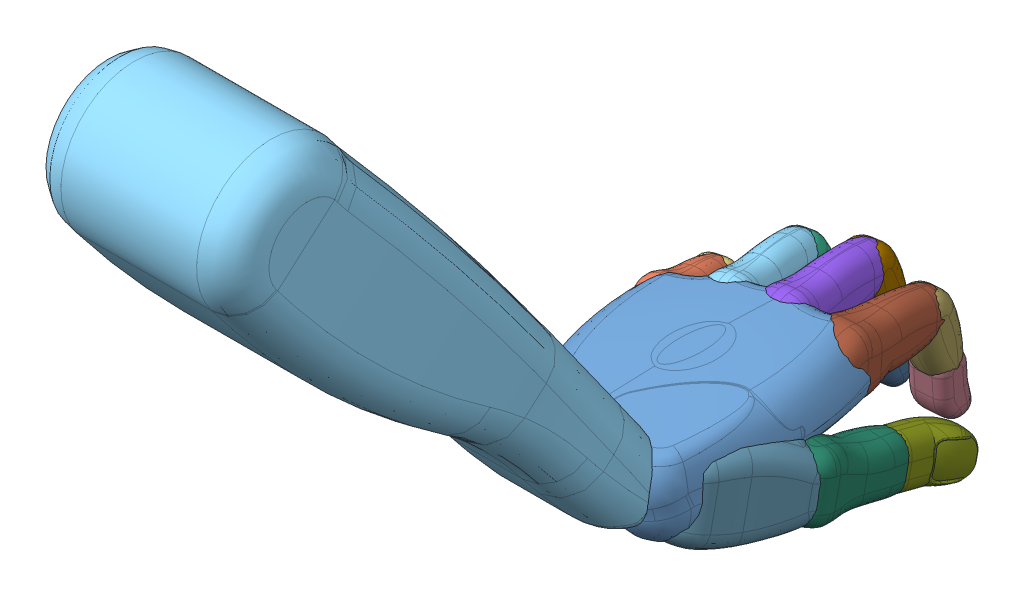
SolidWorks assembly Hand-mit-Arm-5d, configuration Standard. Lengths in mm.
Overall size (132.38 304.77 397.94).
23 component instances, 23 part files, 42 mates.
Components (placement in the parent):
- HF-5d-1: HF-5d [Standard] at origin size (96.85 52.09 117.71)
- K3-1: K3 [Standard] at (10.0992 -18.8586 -82.9973) x (0.966477 0 -0.256752) z (0.251599 0.199354 0.947078) size (27.01 26.01 55)
- K2-1: K2 [Standard] at (1.3242 -26.0179 -116.0285) x (0.966477 0 -0.256752) z (0.11598 0.89216 0.436577) size (16.82 15.68 34)
- K1-1: K1 [Standard] at (-0.9911 -44.6872 -124.7438) x (0.966477 0 -0.256752) z (-0.125162 0.873134 -0.471139) size (16 15.56 30)
- R3-1: R3 [Standard] at (29.3848 -15.1642 -95.2584) x (0.976019 0 -0.217687) z (0.217341 0.056337 0.974469) size (23.74 28.61 65)
- R2-1: R2 [Standard] at (19.9135 -18.8831 -137.7237) x (0.976019 0 -0.217687) z (0.095193 0.899319 0.426807) size (18 19.97 44)
- R1-1: R1 [Standard] at (17.2561 -45.878 -149.6386) x (0.976019 0 -0.217687) z (-0.062668 0.957666 -0.280978) size (18 16.83 32)
- M3-1: M3 [Standard] at (49.8433 -14.9353 -101.0362) x (0.991148 0 -0.132765) z (0.132735 -0.021328 0.990922) size (25.17 30.31 68)
- M2-1: M2 [Standard] at (43.9213 -14.7766 -145.2466) x (0.991148 0 -0.132765) z (0.044526 0.942086 0.332403) size (18.9 20.39 45)
- M1-1: M1 [Standard] at (42.617 -44.2391 -154.9835) x (0.991148 0 -0.132765) z (-0.008324 0.998033 -0.062143) size (18 17.57 33)
- Z3-1: Z3 [Standard] at (73.8939 -17.0937 -102.8961) x (0.997125 0 -0.075768) z (0.07561 0.06453 0.995047) size (27.59 29 66)
- Z2-1: Z2 [Standard] at (70.6409 -20.6053 -145.7063) x (0.997125 0 -0.075768) z (0.022729 0.953944 0.299124) size (18.83 19.55 40)
- Z1-1: Z1 [Standard] at (70.0817 -45.1209 -153.0659) x (0.997125 0 -0.075768) z (0.004903 0.997904 0.064525) size (18 17.52 32)
- D3d-1: D3d [Standard] at (95.0718 -35.7222 -61.2914) x (0 0.978649 -0.205538) z (0.5 -0.178001 -0.847535) size (55.46 56.76 70)
- D2-1: D2 [Standard] at (97.7161 -36.6773 -65.8391) x (0 -0.978649 0.205538) z (-0.061134 0.205153 0.976819) size (31.27 23.91 54)
- D1-1: D1 [Standard] at (100.0697 -44.5757 -103.4467) x (0 -0.978649 0.205538) z (-0.061134 0.205153 0.976819) size (24.93 23.5 40)
- Kugelgelenk-Z-1: Kugelgelenk-Z [Standard] at (74 -15.5 -101.5) x (0.997125 0 -0.075768) z (0.075768 0 0.997125) size (12 12 12)
- Kugelgelenk-K-1: Kugelgelenk-K [Standard] at (10.5 -16.5 -81.4884) x (0.966477 0 -0.256752) z (0.256752 0 0.966477) size (12 12 12)
- Kugelgelenk-M-1: Kugelgelenk-M [Standard] at (50.25 -12 -98) x (0.991148 0 -0.132765) z (0.132765 0 0.991148) size (12 12 12)
- Kugelgelenk-R-1: Kugelgelenk-R [Standard] at (30 -12 -92.5) x (0.976019 0 -0.217687) z (0.217687 0 0.976019) size (12 12 12)
- Kugelgelenk-D-1: Kugelgelenk-D [Standard] at (77 -26 -15) x (1 0 0) z (0 0.205538 0.978649) size (12 12 12)
- Kugelgelenk-H-1: Kugelgelenk-H [Standard] at (52.25 -13.5 -2.5) x (1 0 0) z (0 -0.95434 0.298721) size (12 12 12)
- FUnterarm-V2-1: FUnterarm-V2 [Standard] at (52.25 182.6297 176.1695) x (1 0 0) z (0 0.74849 0.663146) size (110.54 75.93 315.79)
Mates (geometry in assembly coordinates):
- Deckungsgleich1: coincident aligned: circle of K3-1; circle of K2-1
- Deckungsgleich2: coincident aligned: circle of K2-1; circle of K1-1
- Deckungsgleich3: coincident aligned: circle of R2-1; circle of R1-1
- Deckungsgleich4: coincident aligned: circle of R3-1; circle of R2-1
- Deckungsgleich5: coincident aligned: circle of M2-1; circle of M1-1
- Deckungsgleich6: coincident aligned: circle of M3-1; circle of M2-1
- Deckungsgleich7: coincident aligned: circle of Z2-1; circle of Z1-1
- Deckungsgleich8: coincident aligned: circle of Z3-1; circle of Z2-1
- Deckungsgleich9: coincident aligned: circle of D2-1; circle of D1-1
- Deckungsgleich10: coincident aligned: circle of Z3-1; circle of Kugelgelenk-Z-1
- Deckungsgleich11: coincident aligned: circle of HF-5d-1; circle of Kugelgelenk-Z-1
- Deckungsgleich12: coincident aligned: circle of HF-5d-1; circle of Kugelgelenk-K-1
- Deckungsgleich13: coincident aligned: circle of K3-1; circle of Kugelgelenk-K-1
- Deckungsgleich14: coincident aligned: circle of HF-5d-1; circle of Kugelgelenk-M-1
- Deckungsgleich15: coincident aligned: circle of M3-1; circle of Kugelgelenk-M-1
- Deckungsgleich16: coincident aligned: circle of HF-5d-1; circle of Kugelgelenk-R-1
- Deckungsgleich17: coincident aligned: circle of R3-1; circle of Kugelgelenk-R-1
- Deckungsgleich18: coincident anti-aligned: circle of HF-5d-1; circle of Kugelgelenk-D-1
- Deckungsgleich19: coincident anti-aligned: circle of D2-1; circle of D3d-1
- Deckungsgleich20: coincident aligned: circle of Kugelgelenk-D-1; circle of D3d-1
- KurvengetriebeTangential1: cam tangent: cylinder of K1-1 through (3.9273 -38.2245 -109.8742) axis (0.998483 0 -0.055052) radius 0.5; cylinder of K2-1 through (3.8249 -41.7282 -111.7312) axis (0.998483 0 -0.055052) radius 0.5
- KurvengetriebeTangential3: cam tangent: cylinder of R1-1 through (11.8337 -44.5384 -150.9815) axis (0.976019 0 -0.217687) radius 2; cylinder of R2-1 through (11.3443 -43.4452 -153.1759) axis (0.976019 0 -0.217687) radius 0.5
- KurvengetriebeTangential4: cam tangent: cylinder of M1-1 through (37.3796 -42.3685 -156.4224) axis (0.991148 0 -0.132765) radius 2; cylinder of M2-1 through (37.0669 -41.53 -158.7567) axis (0.991148 0 -0.132765) radius 0.5
- KurvengetriebeTangential6: cam tangent: cylinder of Z1-1 through (64.8043 -44.0164 -156.5274) axis (0.997125 0 -0.075768) radius 0.5; cylinder of Z2-1 through (64.8093 -42.777 -156.4608) axis (0.997125 0 -0.075768) radius 0.5
- KurvengetriebeTangential7: cam tangent: cylinder of D1-1 through (101.3529 -38.9456 -100.9657) axis (0 -0.978649 0.205538) radius 2; cylinder of D2-1 through (103.8483 -38.9142 -100.8162) axis (0 -0.978649 0.205538) radius 0.5
- KurvengetriebeTangential8: cam tangent: cylinder of K2-1 through (-4.1374 -24.2167 -117.1132) axis (0.966477 0 -0.256752) radius 0.5; cylinder of K3-1 through (-3.6927 -22.8962 -115.4392) axis (0.966477 0 -0.256752) radius 0.5
- KurvengetriebeTangential9: cam tangent: cylinder of R2-1 through (14.192 -13.1117 -140.4079) axis (0.976019 0 -0.217687) radius 0.5; cylinder of R3-1 through (14.6507 -11.7089 -138.351) axis (0.976019 0 -0.217687) radius 0.5
- KurvengetriebeTangential10: cam tangent: cylinder of M2-1 through (48.3487 -15.6447 -148.1021) axis (0.998081 0 0.06192) radius 0.5; cylinder of M3-1 through (48.3207 -15.5461 -147.6508) axis (0.998081 0 0.06192) radius 0.5
- KurvengetriebeTangential11: cam tangent: cylinder of Z2-1 through (65.3507 -16.7205 -149.3357) axis (0.997125 0 -0.075768) radius 0.5; cylinder of Z3-1 through (65.5192 -14.9757 -147.1185) axis (0.997125 0 -0.075768) radius 0.5
- KurvengetriebeTangential12: cam tangent: cylinder of D2-1 through (100.527 -31.1309 -63.7569) axis (0 -0.978649 0.205538) radius 3; cylinder of D3d-1 through (102.6921 -40.6605 -60.4782) axis (0 0.978649 -0.205538) radius 0.5
- KurvengetriebeTangential13: cam tangent: cylinder of K3-1 through (5.3322 -14.3684 -81.4671) axis (0.966477 0 -0.256752) radius 0.5; cylinder of Kugelgelenk-K-1 through (5.6676 -14 -80.2047) axis (0.966477 0 -0.256752) radius 0.5
- KurvengetriebeTangential14: cam tangent: cylinder of HF-5d-1 through (10.7179 -21.5 -83.9789) axis (0 1 0) radius 0.5; cylinder of Kugelgelenk-K-1 through (10.5 -21.5 -83.9884) axis (0 1 0) radius 0.5
- KurvengetriebeTangential15: cam tangent: cylinder of HF-5d-1 through (30.2179 -17 -94.9905) axis (0 1 0) radius 0.5; cylinder of Kugelgelenk-R-1 through (30 -17 -95) axis (0 1 0) radius 0.5
- KurvengetriebeTangential16: cam tangent: cylinder of HF-5d-1 through (50.25 -7 -98) axis (0 -1 0) radius 3; cylinder of Kugelgelenk-M-1 through (50.25 -17 -100.5) axis (0 1 0) radius 0.5
- KurvengetriebeTangential18: cam tangent: cylinder of R3-1 through (25 -12 -92.5) axis (1 0 0) radius 3; cylinder of Kugelgelenk-R-1 through (25 -9.5 -92.5) axis (1 0 0) radius 0.5
- KurvengetriebeTangential19: cam tangent: cylinder of M3-1 through (45.25 -12 -98) axis (1 0 0) radius 3; cylinder of Kugelgelenk-M-1 through (45.25 -9.5 -98) axis (1 0 0) radius 0.5
- KurvengetriebeTangential21: cam tangent: cylinder of Z3-1 through (69.049 -13.1344 -102.5686) axis (0.998637 0 0.052184) radius 0.5; cylinder of Kugelgelenk-Z-1 through (69.0068 -13 -101.7609) axis (0.998637 0 0.052184) radius 0.5
- KurvengetriebeTangential22: cam tangent: cylinder of HF-5d-1 through (75.25 -10.5 -103.6651) axis (0 -1 0) radius 0.5; cylinder of Kugelgelenk-Z-1 through (74 -20.5 -104) axis (0 1 0) radius 0.5
- KurvengetriebeTangential23: cam tangent: cylinder of HF-5d-1 through (73 -23.5095 -14.7821) axis (1 0 0) radius 0.5; cylinder of Kugelgelenk-D-1 through (73 -23.5007 -15.0608) axis (1 0 0) radius 0.5
- KurvengetriebeTangential24: cam tangent: cylinder of D3d-1 through (77 -30.8932 -13.9723) axis (0 0.978649 -0.205538) radius 3; cylinder of Kugelgelenk-D-1 through (77 -31.4071 -16.4189) axis (0 0.978649 -0.205538) radius 0.5
- Deckungsgleich21: coincident aligned: circle of HF-5d-1; circle of Kugelgelenk-H-1
- Deckungsgleich22: coincident aligned: circle of Kugelgelenk-H-1; circle of FUnterarm-V2-1
